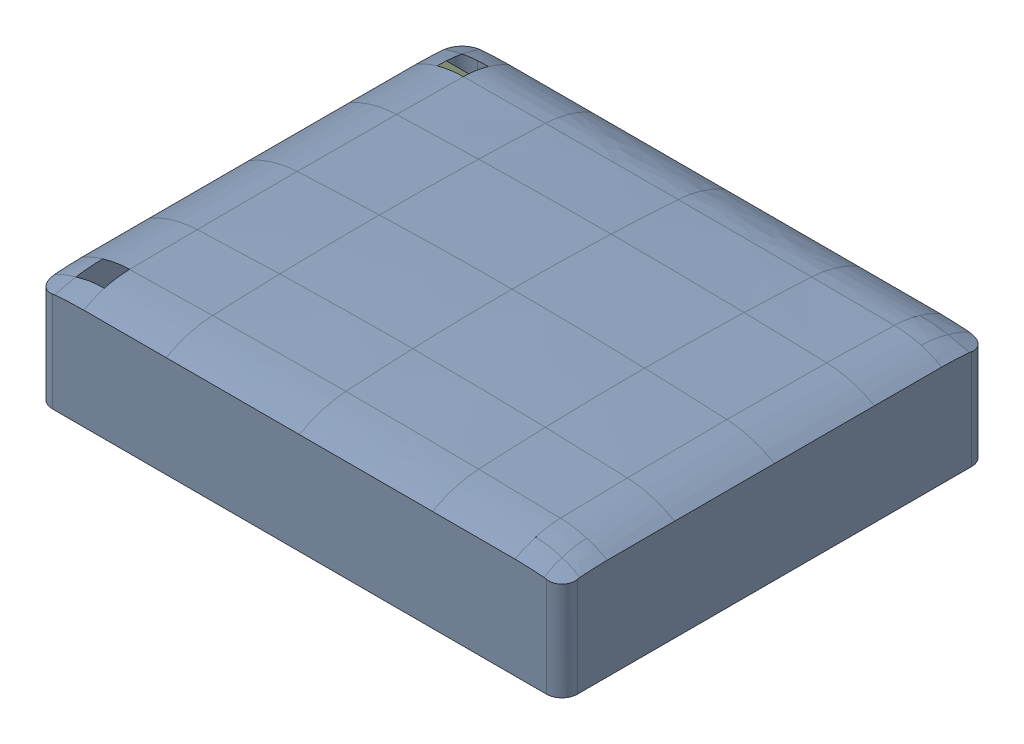
SolidWorks assembly 中间过程Board, configuration 默认. Lengths in mm.
Overall size (23.8 5.48 19.29).
2 component instances, 2 part files, 4 mates.
Components (placement in the parent):
- BoardInsideSkin-1: BoardInsideSkin [默认] at origin size (23.8 5.48 19.29)
- chessboard-1: chessboard [默认] at (-4.7947 23.7 -14.7908) x (1 0 0) z (0 -1 0) size (22.5 16.35 0.4)
Mates (geometry in assembly coordinates):
- 重合1: coordinate: point of BoardInsideSkin-1
- 宽度1: width anti-aligned: plane of BoardInsideSkin-1 through (-11.375 17.7531 -10.075) normal (0 0 -1); plane of chessboard-1 through (-11.375 17.7531 9.075) normal (0 0 1); plane of BoardInsideSkin-1 through (-5.35 23.3 7.675) normal (0 0 1); plane of chessboard-1 through (-7.4 23.3 -8.675) normal (0 0 -1)
- 宽度2: width aligned: plane of BoardInsideSkin-1 through (-12.075 17.7531 -9.375) normal (-1 0 0); plane of chessboard-1 through (11.575 17.7531 -9.375) normal (1 0 0); plane of BoardInsideSkin-1 through (-11.5 23.3 1.525) normal (-1 0 0); plane of chessboard-1 through (11 23.3 -2.575) normal (1 0 0)
- 距离1: distance = 4.3 mm aligned: plane of chessboard-1 through (11.6053 23.3 -6.5908) normal (0 -1 0); plane of BoardInsideSkin-1 through (10.875 19 -9.375) normal (0 -1 0)
